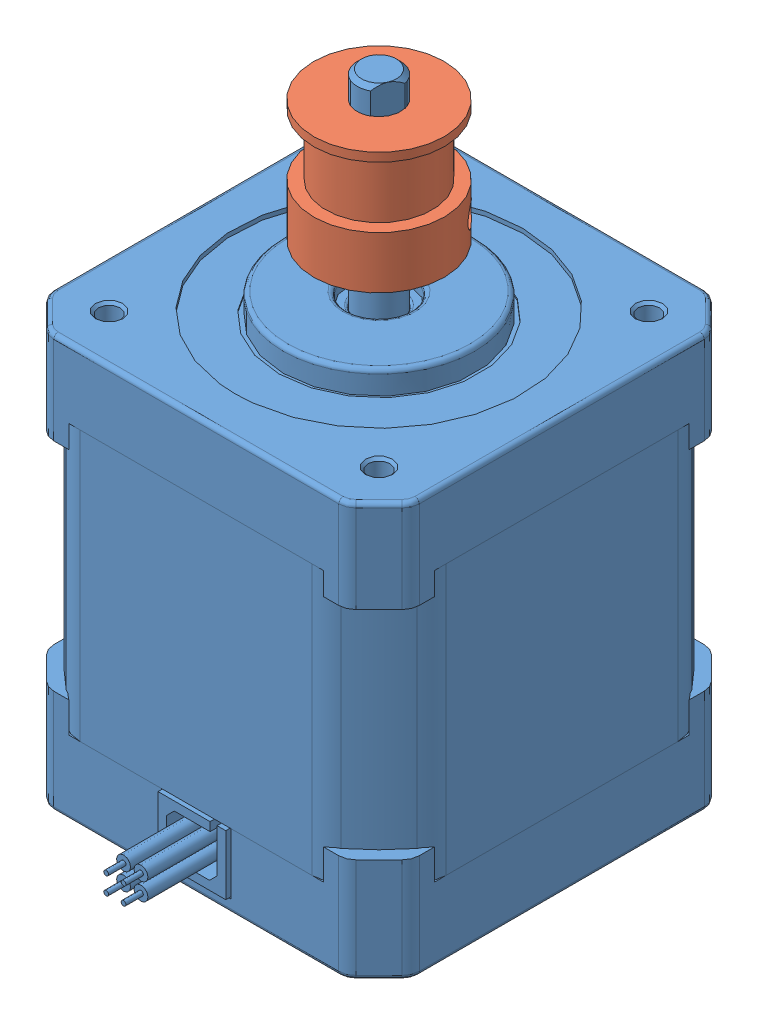
SolidWorks assembly Motor, configuration Default. Lengths in mm.
Overall size (42.48 71.6 51.54).
2 component instances, 2 part files, 5 mates.
Components (placement in the parent):
- Motor_17HM19-2004S-1: Motor_17HM19-2004S [По умолчанию] at (-13.0651 0 1.6976) x (0.999984 0 -0.005702) z (0.005702 0 0.999984) size (42.19 71.6 51.3)
- Motor_GT2 Timing Pulley 20 Tooth-1: Motor_GT2 Timing Pulley 20 Tooth [Default] at (0 54.6 0) x (0 1 0) z (-0.631913 0 -0.775039) size (14 15 15)
Mates (geometry in assembly coordinates):
- Concentric1: concentric: cylinder of Motor_17HM19-2004S-1 through (0 71.6 0) axis (0 -1 0) radius 2.5
- Coincident1: coincident anti-aligned: plane of Motor_17HM19-2004S-1 through (0 0 0) normal (0 -1 0)
- Parallel1: parallel anti-aligned: plane of Motor_17HM19-2004S-1 through (-21 39.5 14.641) normal (-1 0 0)
- Concentric2: concentric anti-aligned: cylinder of Motor_17HM19-2004S-1 through (0 71.6 0) axis (0 -1 0) radius 2.5; cylinder of Motor_GT2 Timing Pulley 20 Tooth-1 through (0 51.1427 0) axis (0 1 0) radius 2.5
- Distance1: distance = 7.5 mm: plane of assembly; plane of assembly; plane of Motor_17HM19-2004S-1 through (0 71.6 0) normal (0 1 0)
